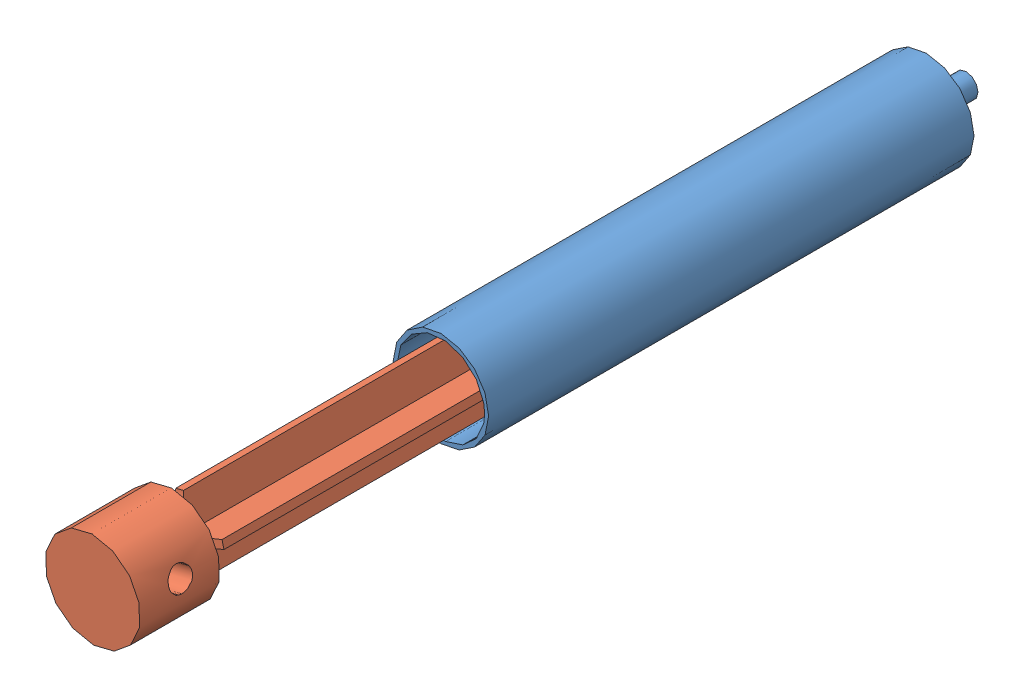
SolidWorks assembly syringe, configuration Default. Lengths in mm.
Overall size (18.45 18.45 139.39).
2 component instances, 2 part files, 3 mates.
Components (placement in the parent):
- sr-cylinder-1: sr-cylinder [Default] at (30.2101 49.0436 27.0158) size (15.24 15.24 83.82)
- sr-plunger-1: sr-plunger [Default] at (30.2101 49.0436 59.7213) x (-0.970784 -0.239954 0) z (0 0 1) size (15.24 15.24 99.06)
Mates (geometry in assembly coordinates):
- Concentric1: concentric: cylinder of sr-cylinder-1 through (30.2101 49.0436 103.2158) axis (0 0 -1) radius 6.985; cylinder of sr-plunger-1 through (30.2101 49.0436 62.2613) axis (0 0 -1) radius 6.985
- LimitDistance1: limit distance = 32.7055 mm: plane of sr-plunger-1 through (30.2101 49.0436 59.7213) normal (0 0 -1); plane of sr-cylinder-1 through (30.2101 49.0436 27.0158) normal (0 0 1)
- Concentric2: concentric aligned: cylinder of sr-cylinder-1 through (30.2101 49.0436 103.2158) axis (0 0 -1) radius 7.62; cylinder of sr-plunger-1 through (30.2101 49.0436 158.7813) axis (0 0 -1) radius 7.62
